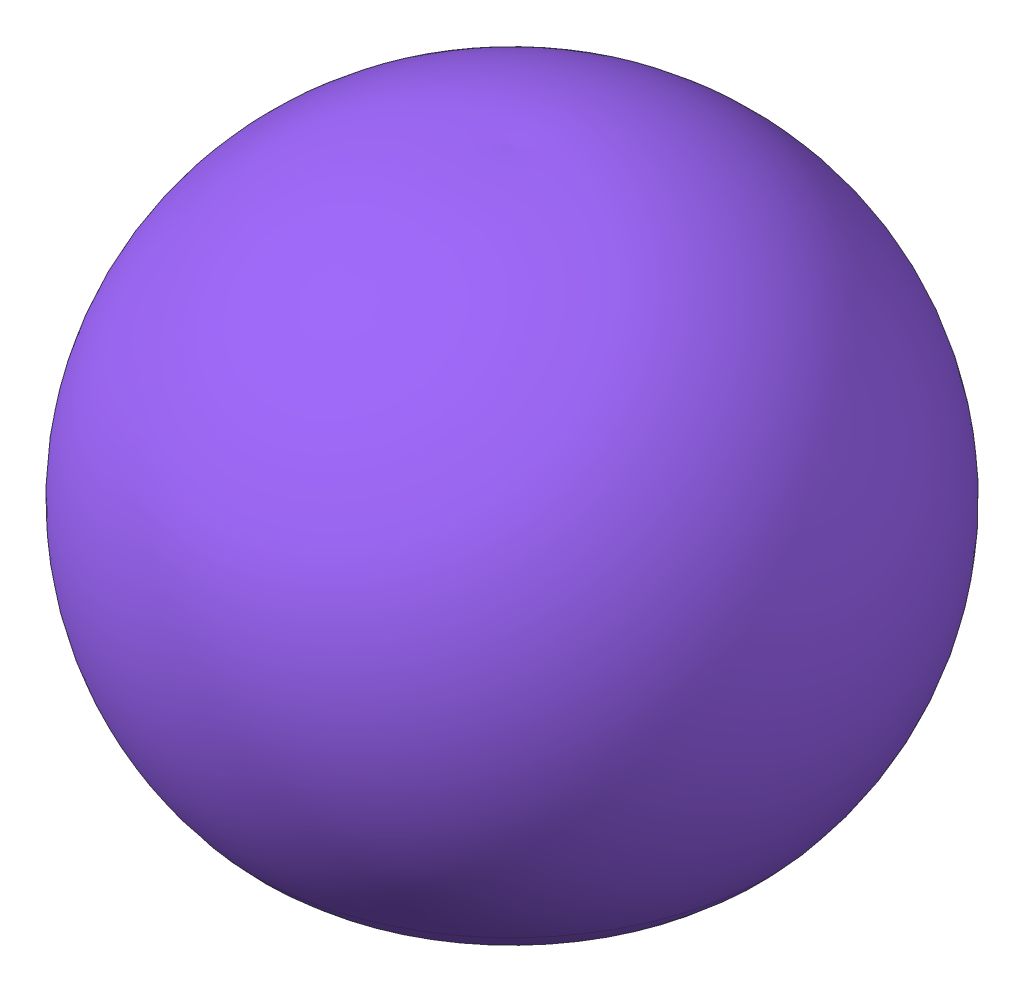
SolidWorks assembly ER16L数模（带配合，SW2015版）, configuration 默认. Lengths in mm.
Overall size (6482.83 5542.73 6482.83).
8 component instances, 8 part files, 13 mates.
Components (placement in the parent):
- 复件 Group13^ER16L数模（带配合，SW2015版）-1: 复件 Group13^ER16L数模（带配合，SW2015版） [默认] at (29.9976 82.2723 354.5704) x (0.999896 0.014415 0) z (0 0 1) size (162 162 1430.5) (virtual)
- 复件 复件 底座^ER16L数模（带配合，SW2015版）-1: 复件 复件 底座^ER16L数模（带配合，SW2015版） [默认] at origin size (620.02 329 655) (virtual)
- 复件 复件 转座^ER16L数模（带配合，SW2015版）-1: 复件 复件 转座^ER16L数模（带配合，SW2015版） [默认] at (0 40 0) size (498.48 520.5 636.76) (virtual)
- 复件 复件 大臂^ER16L数模（带配合，SW2015版）-1: 复件 复件 大臂^ER16L数模（带配合，SW2015版） [默认] at (0 110.4307 -130.3492) x (1 0 0) z (0 -0.243265 0.96996) size (302.19 1673.89 604.74) (virtual)
- 复件 复件 手腕连接体^ER16L数模（带配合，SW2015版）-1: 复件 复件 手腕连接体^ER16L数模（带配合，SW2015版） [默认] at (29.9976 82.2723 354.5704) x (0.999896 0.014415 0) z (0 0 1) size (201.93 149.04 215.3) (virtual)
- 复件 复件 末端法兰^ER16L数模（带配合，SW2015版）-1: 复件 复件 末端法兰^ER16L数模（带配合，SW2015版） [默认] at (-478.6918 4188.1375 354.5704) x (-0.973182 -0.230036 0) z (0 0 1) size (102 102 23.5) (virtual)
- 复件 复件 ER16-C20电机座^ER16L数模（带配合，SW2015版）-1: 复件 复件 ER16-C20电机座^ER16L数模（带配合，SW2015版） [默认] at (0 82.056 340.5704) size (481.1 475 411.67) (virtual)
- 复件 GR6160 3D 包络图^ER16L数模（带配合，SW2015版）-1: 复件 GR6160 3D 包络图^ER16L数模（带配合，SW2015版） [默认] x (-1 0 0) z (0 0 -1) size (6482.83 5542.73 6482.83) (virtual)
Mates (geometry in assembly coordinates):
- 铰链1: hinge anti-aligned: cylinder of 复件 复件 转座^ER16L数模（带配合，SW2015版）-1 through (0 339 0) axis (0 1 0) radius 200; cylinder of 复件 复件 底座^ER16L数模（带配合，SW2015版）-1 through (0 150.5 0) axis (0 -1 0) radius 157.5; plane of 复件 复件 转座^ER16L数模（带配合，SW2015版）-1 through (0 299 0) normal (0 -1 0); plane of 复件 复件 底座^ER16L数模（带配合，SW2015版）-1 through (148.0016 299 53.8682) normal (0 1 0)
- 铰链2: hinge anti-aligned: cylinder of 复件 复件 转座^ER16L数模（带配合，SW2015版）-1 through (200.9335 603 220) axis (1 0 0) radius 141.75; cylinder of 复件 复件 大臂^ER16L数模（带配合，SW2015版）-1 through (167.5 603 220) axis (-1 0 0) radius 122.5; plane of 复件 复件 大臂^ER16L数模（带配合，SW2015版）-1 through (167.5 603 220) normal (-1 0 0); plane of 复件 复件 转座^ER16L数模（带配合，SW2015版）-1 through (167.5 603 97.5) normal (1 0 0)
- 铰链3: hinge anti-aligned: cylinder of 复件 复件 大臂^ER16L数模（带配合，SW2015版）-1 through (182.9 2003 220) axis (-1 0 0) radius 104; cylinder of 复件 复件 ER16-C20电机座^ER16L数模（带配合，SW2015版）-1 through (107.9 2003 220) axis (-1 0 0) radius 93; plane of 复件 复件 ER16-C20电机座^ER16L数模（带配合，SW2015版）-1 through (182.9 2003 220) normal (1 0 0); plane of 复件 复件 大臂^ER16L数模（带配合，SW2015版）-1 through (182.9 2003 220) normal (-1 0 0)
- 铰链4: hinge anti-aligned: cylinder of 复件 复件 ER16-C20电机座^ER16L数模（带配合，SW2015版）-1 through (0 2163 401.5) axis (0 0 -1) radius 70; cylinder of 复件 Group13^ER16L数模（带配合，SW2015版）-1 through (0 2163 487.5) axis (0 0 1) radius 80; plane of 复件 复件 ER16-C20电机座^ER16L数模（带配合，SW2015版）-1 through (0 2163 479.5) normal (0 0 1); plane of 复件 Group13^ER16L数模（带配合，SW2015版）-1 through (0 2163 479.5) normal (0 0 -1)
- 同心2: concentric anti-aligned: cylinder of 复件 Group13^ER16L数模（带配合，SW2015版）-1 through (-63.1 2163 1847.5) axis (1 0 0) radius 55; cylinder of 复件 复件 手腕连接体^ER16L数模（带配合，SW2015版）-1 through (-64.6 2163 1847.5) axis (-1 0 0) radius 59
- 距离1: distance = 16.5 mm anti-aligned: plane of 复件 Group13^ER16L数模（带配合，SW2015版）-1 through (-63.1 2210.3822 1848.7974) normal (-1 0 0); plane of 复件 复件 手腕连接体^ER16L数模（带配合，SW2015版）-1 through (-79.6 2163 1847.5) normal (1 0 0)
- 铰链6: hinge anti-aligned: cylinder of 复件 复件 手腕连接体^ER16L数模（带配合，SW2015版）-1 through (0 2163 1979.8) axis (0 0 -1) radius 51; cylinder of 复件 复件 末端法兰^ER16L数模（带配合，SW2015版）-1 through (0 2163 2000.8) axis (0 0 1) radius 51; plane of 复件 复件 手腕连接体^ER16L数模（带配合，SW2015版）-1 through (0 2163 1992.8) normal (0 0 1); plane of 复件 复件 末端法兰^ER16L数模（带配合，SW2015版）-1 through (0 2163 1992.8) normal (0 0 -1)
- 平行1: parallel aligned: plane of 复件 复件 底座^ER16L数模（带配合，SW2015版）-1 through (-300 30 300) normal (-1 0 0); plane of 复件 复件 转座^ER16L数模（带配合，SW2015版）-1 through (-217.16 720 5.5374) normal (-1 0 0)
- 平行2: parallel aligned: plane of 复件 复件 转座^ER16L数模（带配合，SW2015版）-1 through (-274 653 315) normal (0 0 1); plane of 复件 复件 大臂^ER16L数模（带配合，SW2015版）-1 through (125 848.6669 219.5) normal (0 0 1)
- 重合3: coincident aligned: plane of 复件 复件 大臂^ER16L数模（带配合，SW2015版）-1 through (165.1064 2003.5 338) normal (0 -1 0); plane of 复件 复件 ER16-C20电机座^ER16L数模（带配合，SW2015版）-1 through (161 2003.5 357.8716) normal (0 -1 0)
- 平行3: parallel aligned: plane of 复件 Group13^ER16L数模（带配合，SW2015版）-1 through (20 2223 672.5) normal (0 1 0); plane of 复件 复件 ER16-C20电机座^ER16L数模（带配合，SW2015版）-1 through (60 2298 315) normal (0 1 0)
- 重合5: coincident aligned: plane of 复件 Group13^ER16L数模（带配合，SW2015版）-1 through (50 2162.5 1791.4076) normal (0 1 0); plane of 复件 复件 手腕连接体^ER16L数模（带配合，SW2015版）-1 through (56.1347 2162.5 1791.5) normal (0 1 0)
- 重合6: coincident aligned: plane of 复件 复件 手腕连接体^ER16L数模（带配合，SW2015版）-1 through (-2.9024 2112.5835 1996.8) normal (-0.893331 -0.4494 0); plane of 复件 复件 末端法兰^ER16L数模（带配合，SW2015版）-1 through (-2.4083 2111.6013 1983.8) normal (-0.893331 -0.4494 0)
